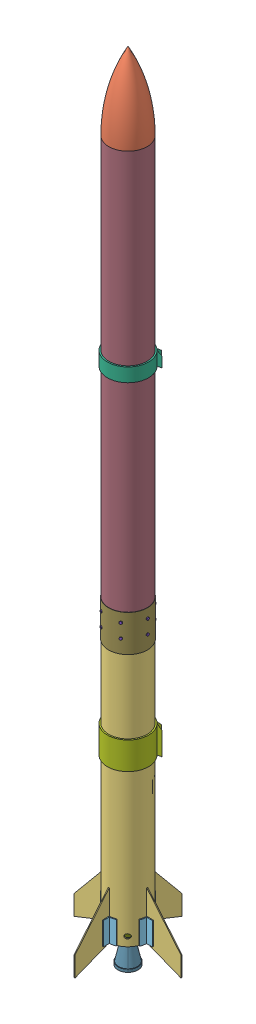
SolidWorks assembly Fiberglass Assembly, configuration Default. Lengths in mm.
Overall size (234 1742.58 234).
100 component instances, 30 part files, 23 mates.
Components (placement in the parent):
- Avionics bay base_Fiberglass-1: Avionics bay base_Fiberglass [Default] at (551.3676 29.2002 -432.6832) x (0 1 0) z (0.866025 0 0.5) size (45 80 80)
- Bulkhead_Fiberglass-1: Bulkhead_Fiberglass [Default] at (551.3676 -25.7998 -432.6832) x (0 1 0) z (0.77729 0 -0.629143) size (34.4 80 80)
- Final_assemblyv2_v9_Fiberglass.step-1: Final_assemblyv2_v9_Fiberglass.step [Default] at (551.6157 91.6002 -431.2714) x (0.94257 0 0.334009) z (0 1 0) size (79 77.25 403.33)
  - Holder Avionics Bay.step-1: Holder Avionics Bay.step [Default] at origin size (79 77.25 25)
  - holder_rod.step-1: holder_rod.step [Default] at (-20 -25 -20) size (11.8 11.8 400)
  - holder_rod.step-2: holder_rod.step [Default] at (-20 25 -20) size (11.8 11.8 400)
  - holder_rod.step-3: holder_rod.step [Default] at (20 -25 -20) size (11.8 11.8 400)
  - holder_rod.step-4: holder_rod.step [Default] at (20 25 -20) size (11.8 11.8 400)
  - Holder Avionics Bay v5(Mirror).step-1: Holder Avionics Bay v5(Mirror).step [Default] at (0 0 360) size (79 77.25 45)
  - bottom compartment.step-1: bottom compartment.step [Default] at (0 0 15) size (70 65 10)
  - Bottom coupler.step-1: Bottom coupler.step [Default] at (0 0 55) size (70 65 10)
  - bottom compartment v11(Mirror).step-1: bottom compartment v11(Mirror).step [Default] at (0 0 345) size (70 65 10) (hidden)
  - Bottom coupler v4(Mirror).step-1: Bottom coupler v4(Mirror).step [Default] at (0 0 305) size (70 65 10)
  - Ebay.step-1: Ebay.step [Default] at (-24.7152 -0.1039 65) x (0 -1 0) z (0 0 1) size (37.59 17.04 270)
  - Ebay.step-2: Ebay.step [Default] at (23.6609 1.1098 65) x (0 1 0) z (0 0 1) size (37.59 17.04 270)
  - holder_nut.step-1: holder_nut.step [Default] at (-19.7125 -25.3564 27) size (16 18.48 5)
  - holder_nut.step-2: holder_nut.step [Default] at (22.0357 -23.0001 27) size (16 18.48 5) (hidden)
  - holder_nut.step-3: holder_nut.step [Default] at (21.9624 25.8778 27) size (16 18.48 5) (hidden)
  - holder_nut.step-4: holder_nut.step [Default] at (-19.7125 24.6436 27) size (16 18.48 5)
  - holder_nut.step-5: holder_nut.step [Default] at (21.4998 -25.6594 10) size (16 18.48 5) (hidden)
  - holder_nut.step-6: holder_nut.step [Default] at (-19.7125 -25.3564 10) size (16 18.48 5)
  - holder_nut.step-7: holder_nut.step [Default] at (-19.7125 25.6436 10) size (16 18.48 5)
  - holder_nut.step-8: holder_nut.step [Default] at (21.4998 25.3406 10) size (16 18.48 5) (hidden)
  - holder_nut.step-9: holder_nut.step [Default] at (-20 25 305) size (16 18.48 5)
  - holder_nut.step-10: holder_nut.step [Default] at (20 -25 306) size (16 18.48 5)
  - holder_nut.step-11: holder_nut.step [Default] at (20 25 306) size (16 18.48 5)
  - holder_nut.step-12: holder_nut.step [Default] at (20 -25 329) size (16 18.48 5)
  - holder_nut.step-13: holder_nut.step [Default] at (-20 25 330) size (16 18.48 5)
  - holder_nut.step-14: holder_nut.step [Default] at (-20 -25 305) size (16 18.48 5)
  - holder_nut.step-15: holder_nut.step [Default] at (-20 -25 330) size (16 18.48 5)
  - holder_nut.step-16: holder_nut.step [Default] at (-20 -25 345) size (16 18.48 5)
  - holder_nut.step-17: holder_nut.step [Default] at (-20 25 345) size (16 18.48 5)
  - holder_nut.step-18: holder_nut.step [Default] at (20 25 330) size (16 18.48 5)
  - holder_nut.step-19: holder_nut.step [Default] at (20 25 345) size (16 18.48 5)
  - holder_nut.step-20: holder_nut.step [Default] at (20 -25 345) size (16 18.48 5)
  - holder_nut.step-21: holder_nut.step [Default] at (20 -25 360) size (16 18.48 5)
  - holder_nut.step-22: holder_nut.step [Default] at (-20 -25 360) size (16 18.48 5)
  - holder_nut.step-23: holder_nut.step [Default] at (-20 25 360) size (16 18.48 5)
  - holder_nut.step-24: holder_nut.step [Default] at (20 25 360) size (16 18.48 5)
  - holder_nut.step-25: holder_nut.step [Default] at (-20 25 0) x (1 0 0) z (0 0 -1) size (16 18.48 5)
  - holder_nut.step-26: holder_nut.step [Default] at (20 25 0) x (1 0 0) z (0 0 -1) size (16 18.48 5)
  - holder_nut.step-27: holder_nut.step [Default] at (20 -25 0) x (1 0 0) z (0 0 -1) size (16 18.48 5)
  - holder_nut.step-28: holder_nut.step [Default] at (-20 -25 0) x (1 0 0) z (0 0 -1) size (16 18.48 5)
  - assemblyv2.step-1: assemblyv2.step [Default] at origin size (25.28 25.75 8.33)
- Main body to tail coupler_V2-1: Main body to tail coupler_V2 [Default] at (551.3676 14.2002 -432.6832) x (0 1 0) z (0 0 1) size (80 85 85)
- Main Body_Fiberglass-1: Main Body_Fiberglass [Default] at (551.3676 484.2002 -432.6832) x (1 0 0) z (0 -1 0) size (84 84 910)
- motor1_Fiberglass-1: motor1_Fiberglass [Default] at (1723.644 -358.3506 -188.3764) x (0 -1 0) z (-0.716244 0 -0.69785) size (597.58 104.34 104.34)
  - motor1.STEP-1: motor1.STEP [Default] at origin size (597.58 104.34 104.34)
    - nozzle3.STEP-1: nozzle3.STEP [Default] at (-86.2279 353.0891 1010.1259) size (104.18 70 70)
    - socket head cap screw_am2_B18.3.1M - 24 x 3.0 x 70 Hex SHCS -- 70NHX.STEP-1: socket head cap screw_am2_B18.3.1M - 24 x 3.0 x 70 Hex SHCS -- 70NHX.STEP [Default] at (186.0687 709.2264 971.9415) x (0 -0.866025 0.5) z (0.913194 0.203763 0.352927) size (9.4 3.6 3.6)
    - casing.STEP-1: casing.STEP [Default] at (-322.5508 643.0891 1010.1259) x (0 -0.568389 -0.82276) z (1 0 0) size (75 75 520)
    - socket head cap screw_am2_B18.3.1M - 24 x 3.0 x 70 Hex SHCS -- 70NHX.STEP-2: socket head cap screw_am2_B18.3.1M - 24 x 3.0 x 70 Hex SHCS -- 70NHX.STEP [Default] at (186.0687 709.2264 1048.3103) x (0 -0.866025 -0.5) z (0.855581 0.258835 -0.448315) size (9.4 3.6 3.6)
    - socket head cap screw_am2_B18.3.1M - 24 x 3.0 x 70 Hex SHCS -- 70NHX.STEP-3: socket head cap screw_am2_B18.3.1M - 24 x 3.0 x 70 Hex SHCS -- 70NHX.STEP [Default] at (186.0687 681.2735 1076.2632) x (0 -0.5 -0.866025) z (-0.328816 -0.817869 0.472197) size (9.4 3.6 3.6)
    - socket head cap screw_am2_B18.3.1M - 24 x 3.0 x 70 Hex SHCS -- 70NHX.STEP-4: socket head cap screw_am2_B18.3.1M - 24 x 3.0 x 70 Hex SHCS -- 70NHX.STEP [Default] at (186.0687 643.0891 1086.4947) x (0 0 -1) z (0.63325 -0.773947 0) size (9.4 3.6 3.6)
    - socket head cap screw_am2_B18.3.1M - 24 x 3.0 x 70 Hex SHCS -- 70NHX.STEP-5: socket head cap screw_am2_B18.3.1M - 24 x 3.0 x 70 Hex SHCS -- 70NHX.STEP [Default] at (186.0687 604.9047 1076.2632) x (0 0.5 -0.866025) z (0.63325 -0.670258 -0.386974) size (9.4 3.6 3.6)
    - socket head cap screw_am2_B18.3.1M - 24 x 3.0 x 70 Hex SHCS -- 70NHX.STEP-6: socket head cap screw_am2_B18.3.1M - 24 x 3.0 x 70 Hex SHCS -- 70NHX.STEP [Default] at (186.0687 576.9517 1048.3103) x (0 0.866025 -0.5) z (0.63325 -0.386974 -0.670258) size (9.4 3.6 3.6)
    - socket head cap screw_am2_B18.3.1M - 24 x 3.0 x 70 Hex SHCS -- 70NHX.STEP-7: socket head cap screw_am2_B18.3.1M - 24 x 3.0 x 70 Hex SHCS -- 70NHX.STEP [Default] at (186.0687 566.7203 1010.1259) x (0 1 0) z (0.63325 0 -0.773947) size (9.4 3.6 3.6)
    - socket head cap screw_am2_B18.3.1M - 24 x 3.0 x 70 Hex SHCS -- 70NHX.STEP-8: socket head cap screw_am2_B18.3.1M - 24 x 3.0 x 70 Hex SHCS -- 70NHX.STEP [Default] at (186.0687 576.9517 971.9415) x (0 0.866025 0.5) z (0.63325 0.386974 -0.670258) size (9.4 3.6 3.6)
    - socket head cap screw_am2_B18.3.1M - 24 x 3.0 x 70 Hex SHCS -- 70NHX.STEP-9: socket head cap screw_am2_B18.3.1M - 24 x 3.0 x 70 Hex SHCS -- 70NHX.STEP [Default] at (186.0687 643.0891 933.7571) x (0 0 1) z (0.63325 0.773947 0) size (9.4 3.6 3.6)
    - socket head cap screw_am2_B18.3.1M - 24 x 3.0 x 70 Hex SHCS -- 70NHX.STEP-10: socket head cap screw_am2_B18.3.1M - 24 x 3.0 x 70 Hex SHCS -- 70NHX.STEP [Default] at (186.0687 681.2735 943.9885) x (0 -0.5 0.866025) z (0.63325 0.670258 0.386974) size (9.4 3.6 3.6)
    - socket head cap screw_am2_B18.3.1M - 24 x 3.0 x 70 Hex SHCS -- 70NHX.STEP-11: socket head cap screw_am2_B18.3.1M - 24 x 3.0 x 70 Hex SHCS -- 70NHX.STEP [Default] at (186.0687 604.9047 943.9885) x (0 0.5 0.866025) z (0.754615 0.568258 -0.328084) size (9.4 3.6 3.6)
    - spacer.STEP-1: spacer.STEP [Default] at (170.8487 643.0891 1010.1259) x (0 0.405549 -0.914073) z (0 0.914073 0.405549) size (66 6 66)
    - propellant.STEP-1: propellant.STEP [Default] at (62.8487 643.0891 1010.1259) x (0 0 -1) z (1 0 0) size (66 66 102)
    - spacer.STEP-2: spacer.STEP [Default] at (62.8487 643.0891 1010.1259) x (0 0.405549 -0.914073) z (0 0.914073 0.405549) size (66 6 66)
    - propellant.STEP-2: propellant.STEP [Default] at (-45.1513 643.0891 1010.1259) x (0 0.960645 -0.277778) z (1 0 0) size (66 66 102)
    - spacer.STEP-3: spacer.STEP [Default] at (-51.1513 643.0891 1010.1259) x (0 -0.456603 -0.88967) z (0 -0.88967 0.456603) size (66 6 66)
    - propellant.STEP-3: propellant.STEP [Default] at (-153.1513 643.0891 1010.1259) x (0 -0.636867 0.770973) z (1 0 0) size (66 66 102)
    - spacer.STEP-4: spacer.STEP [Default] at (-159.1513 643.0891 1010.1259) x (0 -0.456603 -0.88967) z (0 -0.88967 0.456603) size (66 6 66)
    - propellant.STEP-4: propellant.STEP [Default] at (-261.1513 643.0891 1010.1259) x (0 -0.636867 0.770973) z (1 0 0) size (66 66 102)
    - spacer.STEP-5: spacer.STEP [Default] at (-267.1513 643.0891 1010.1259) x (0 0.156993 -0.9876) z (0 -0.9876 -0.156993) size (66 6 66)
    - bulkhead.STEP-1: bulkhead.STEP [Default] at (-307.1513 633.6442 1033.2731) x (0 0.92589 0.377793) z (-1 0 0) size (70 70 40)
    - socket head cap screw_am2_B18.3.1M - 24 x 3.0 x 70 Hex SHCS -- 70NHX.STEP-12: socket head cap screw_am2_B18.3.1M - 24 x 3.0 x 70 Hex SHCS -- 70NHX.STEP [Default] at (186.0687 717.7199 1010.1259) x (0 -1 0) z (-0.574536 0 -0.818479) size (9.4 3.6 3.6) (hidden)
    - liner.STEP-1: liner.STEP [Default] at (-267.1513 643.0891 1010.1259) x (0 -0.411382 -0.911463) z (1 0 0) size (70 70 438) (hidden)
- Nosecone_Fiberglass-1: Nosecone_Fiberglass [Default] at (551.3676 939.2002 -432.6832) x (0.057838 0 -0.998326) z (0 -1 0) size (84 84 220)
- Tail Tube_Fiberglass-1: Tail Tube_Fiberglass [Default] at (551.3676 -570.7998 -432.6832) x (1 0 0) z (0 1 0) size (234 234 629.7)
- Top Avionics Attachment_Fiberglass-1: Top Avionics Attachment_Fiberglass [Default] at (551.3676 484.2002 -432.6832) x (-0.930043 0 -0.367452) z (0 -1 0) size (76 76 10)
- Tail Attachment-4: Tail Attachment [Default] at (551.3676 -520.8528 -432.6832) x (-1 0 0) z (0 -1 0) size (14.71 17.76 50)
- Tail Attachment-5: Tail Attachment [Default] at (551.3676 -570.4701 -432.6832) x (1 0 0) z (0 1 0) size (14.71 17.76 50)
- Launch Lug-1: Launch Lug [Default] at (551.3676 501.9114 -432.6832) x (0.740135 0 0.672458) z (0 1 0) size (90 97 30)
- Launch Lug_Tail-1: Launch Lug_Tail [Default] at (551.3676 -236.0889 -432.6832) x (0.740135 0 0.672458) z (0 1 0) size (90 97 60)
- M4_Bolts-1: M4_Bolts [Default] at (529.3032 14.2002 -470.8999) x (0.164902 0.981704 -0.095206) z (0.5 0 0.866025) size (5.23 5.75 17)
- M4_Bolts-2: M4_Bolts [Default] at (573.432 14.2002 -470.8999) x (0.164902 0.981704 0.095206) z (-0.5 0 0.866025) size (5.23 5.75 17)
- M4_Bolts-3: M4_Bolts [Default] at (595.4964 14.2002 -432.6832) x (0 0.981704 0.190413) z (-1 0 0) size (5.23 5.75 17)
- M4_Bolts-4: M4_Bolts [Default] at (573.432 14.2002 -394.4666) x (-0.164902 0.981704 0.095206) z (-0.5 0 -0.866025) size (5.23 5.75 17)
- M4_Bolts-5: M4_Bolts [Default] at (529.3032 14.2002 -394.4666) x (-0.164902 0.981704 -0.095206) z (0.5 0 -0.866025) size (5.23 5.75 17)
- M4_Bolts-6: M4_Bolts [Default] at (507.2388 14.2002 -432.6832) x (0 0.981704 -0.190413) z (1 0 0) size (5.23 5.75 17)
- M4_Bolts-7: M4_Bolts [Default] at (529.2619 44.2002 -470.9714) x (0.865813 -0.022132 -0.499878) z (0.5 0 0.866025) size (5.23 5.75 17)
- M4_Bolts-8: M4_Bolts [Default] at (573.4733 44.2002 -470.9714) x (0.865813 -0.022132 0.499878) z (-0.5 0 0.866025) size (5.23 5.75 17)
- M4_Bolts-9: M4_Bolts [Default] at (595.579 44.2002 -432.6832) x (0 -0.022132 0.999755) z (-1 0 0) size (5.23 5.75 17)
- M4_Bolts-10: M4_Bolts [Default] at (573.4733 44.2002 -394.3951) x (-0.865813 -0.022132 0.499878) z (-0.5 0 -0.866025) size (5.23 5.75 17)
- M4_Bolts-11: M4_Bolts [Default] at (529.2619 44.2002 -394.3951) x (-0.865813 -0.022132 -0.499878) z (0.5 0 -0.866025) size (5.23 5.75 17)
- M4_Bolts-12: M4_Bolts [Default] at (507.1562 44.2002 -432.6832) x (0 -0.022132 -0.999755) z (1 0 0) size (5.23 5.75 17)
- Tail Attachment-6: Tail Attachment [Default] at (551.3676 -520.8528 -432.6832) x (0 0 1) z (0 -1 0) size (14.71 17.76 50)
- Tail Attachment-7: Tail Attachment [Default] at (551.3676 -520.8528 -432.6832) x (1 0 0) z (0 -1 0) size (14.71 17.76 50)
- Tail Attachment-8: Tail Attachment [Default] at (551.3676 -520.8528 -432.6832) x (0 0 -1) z (0 -1 0) size (14.71 17.76 50)
- Tail Attachment-9: Tail Attachment [Default] at (551.3676 -570.4701 -432.6832) x (0 0 -1) z (0 1 0) size (14.71 17.76 50)
- Tail Attachment-10: Tail Attachment [Default] at (551.3676 -570.4701 -432.6832) x (-1 0 0) z (0 1 0) size (14.71 17.76 50)
- Tail Attachment-11: Tail Attachment [Default] at (551.3676 -570.4701 -432.6832) x (0 0 1) z (0 1 0) size (14.71 17.76 50)
- Ejection-1: Ejection [Default] at (551.3676 544.0326 -432.6832) x (0.791016 0 -0.611795) z (0.611795 0 0.791016) size (79 159 79)
- Parachute cup-1: Parachute cup [Default] at (551.3676 709.1474 -432.6832) x (0.973006 0 0.230779) z (-0.230779 0 0.973006) size (79 173 79)
Mates (geometry in assembly coordinates):
- Concentric1: concentric aligned: cylinder of Bulkhead_Fiberglass-1 through (551.3676 -50.1998 -432.6832) axis (0 1 0) radius 35; cylinder of motor1_Fiberglass-1/motor1.STEP-1/casing.STEP-1 through (551.3676 -555.7998 -432.6832) axis (0 1 0) radius 35
- Coincident1: coincident anti-aligned: plane of Bulkhead_Fiberglass-1 through (551.3676 -35.7998 -432.6832) normal (0 -1 0); plane of motor1_Fiberglass-1/motor1.STEP-1/casing.STEP-1 through (551.3676 -35.7998 -432.6832) normal (0 1 0)
- Concentric4: concentric anti-aligned: cylinder of Avionics bay base_Fiberglass-1 through (551.3676 64.2002 -432.6832) axis (0 -1 0) radius 35; cylinder of Main body to tail coupler_Fiberglass-1 through (551.3676 29.2002 -432.6832) axis (0 1 0) radius 40
- Concentric5: concentric: cylinder of Avionics bay base_Fiberglass-1 through (576.3676 44.2002 -432.6832) axis (1 0 0) radius 2; cylinder of Main body to tail coupler_Fiberglass-1 through (511.3666 44.2002 -432.6832) axis (1 0 0) radius 2
- Coincident3: coincident anti-aligned: circle of Main Body_Fiberglass-1; circle of Tail Tube_Fiberglass-1
- Concentric6: concentric anti-aligned: cylinder of Main Body_Fiberglass-1 through (551.3676 939.2002 -432.6832) axis (0 -1 0) radius 40; cylinder of Nosecone_Fiberglass-1 through (551.3676 889.2002 -432.6832) axis (0 1 0) radius 40
- Coincident4: coincident anti-aligned: plane of Main Body_Fiberglass-1 through (551.3676 939.2002 -432.6832) normal (0 1 0); plane of Nosecone_Fiberglass-1 through (551.3676 939.2002 -432.6832) normal (0 -1 0)
- Concentric7: concentric anti-aligned: cylinder of Main Body_Fiberglass-1 through (551.3676 939.2002 -432.6832) axis (0 -1 0) radius 40; cylinder of Top Avionics Attachment_Fiberglass-1 through (551.3676 474.2002 -432.6832) axis (0 1 0) radius 38
- Distance1: distance = 400 mm anti-aligned: plane of Top Avionics Attachment_Fiberglass-1 through (551.3676 474.2002 -432.6832) normal (0 -1 0); plane of Avionics bay base_Fiberglass-1 through (551.3676 74.2002 -432.6832) normal (0 1 0)
- Concentric23: concentric aligned: cylinder of Main Body_Fiberglass-1 through (551.3676 939.2002 -432.6832) axis (0 -1 0) radius 42; cylinder of Launch Lug-1 through (551.3676 531.9114 -432.6832) axis (0 -1 0) radius 42
- Concentric26: concentric: cylinder of Main body to tail coupler_Fiberglass-1 through (551.3676 -35.7998 -432.6832) axis (0 1 0) radius 38; cylinder of Main Body_Fiberglass-1 through (551.3676 939.2002 -432.6832) axis (0 -1 0) radius 40
- Concentric27: concentric: cylinder of Main body to tail coupler_Fiberglass-1 through (511.3666 44.2002 -432.6832) axis (1 0 0) radius 2; cylinder of Main Body_Fiberglass-1 through (509.3666 44.2002 -432.6832) axis (1 0 0) radius 2
- Concentric29: concentric: cylinder of Main body to tail coupler_Fiberglass-1 through (538.8676 14.2002 -454.3339) axis (-0.5 0 -0.866025) radius 2; cylinder of Tail Tube_Fiberglass-1 through (580.0548 14.2002 -382.9955) axis (-0.5 0 -0.866025) radius 2
- Concentric30: concentric: cylinder of Main body to tail coupler_Fiberglass-1 through (538.8676 14.2002 -454.3339) axis (-0.5 0 -0.866025) radius 2; cylinder of M4_Bolts-1 through (537.8032 14.2002 -456.1775) axis (-0.5 0 -0.866025) radius 2
- Concentric31: concentric aligned: cylinder of Avionics bay base_Fiberglass-1 through (538.8676 44.2002 -454.3339) axis (-0.5 0 -0.866025) radius 2; cylinder of M4_Bolts-7 through (537.7619 44.2002 -456.249) axis (-0.5 0 -0.866025) radius 2
- Concentric33: concentric anti-aligned: cylinder of Tail Tube_Fiberglass-1 through (551.3676 29.2002 -432.6832) axis (0 -1 0) radius 42; cylinder of Tail Attachment-4 through (551.3676 -570.8528 -432.6832) axis (0 1 0) radius 42
- Coincident5: coincident anti-aligned: plane of Tail Tube_Fiberglass-1 through (552.3676 -570.7998 -432.6832) normal (1 0 0); plane of Tail Attachment-4 through (552.3676 -570.8528 -474.6713) normal (-1 0 0)
- Concentric34: concentric aligned: cylinder of Tail Tube_Fiberglass-1 through (551.3676 29.2002 -432.6832) axis (0 -1 0) radius 42; cylinder of Tail Attachment-5 through (551.3676 -520.4701 -432.6832) axis (0 -1 0) radius 42
- Coincident6: coincident anti-aligned: plane of Tail Tube_Fiberglass-1 through (550.3676 -570.7998 -432.6832) normal (-1 0 0); plane of Tail Attachment-5 through (550.3676 -520.4701 -474.6713) normal (1 0 0)
- Concentric35: concentric aligned: cylinder of Tail Tube_Fiberglass-1 through (551.3676 29.2002 -432.6832) axis (0 -1 0) radius 42; cylinder of Launch Lug_Tail-1 through (551.3676 -176.0889 -432.6832) axis (0 -1 0) radius 42
- Parallel1: parallel aligned: plane of Launch Lug-1 through (586.3354 531.9114 -471.1703) normal (0.672458 0 -0.740135); plane of Launch Lug_Tail-1 through (586.3354 -176.0889 -471.1703) normal (0.672458 0 -0.740135)
- Concentric36: concentric aligned: cylinder of Main Body_Fiberglass-1 through (551.3676 939.2002 -432.6832) axis (0 -1 0) radius 42; cylinder of Parachute cup-1 through (551.3676 882.1474 -432.6832) axis (0 -1 0) radius 39.5
- Concentric37: concentric aligned: cylinder of Main Body_Fiberglass-1 through (551.3676 939.2002 -432.6832) axis (0 -1 0) radius 42; cylinder of Ejection-1 through (551.3676 703.0326 -432.6832) axis (0 -1 0) radius 39.5
